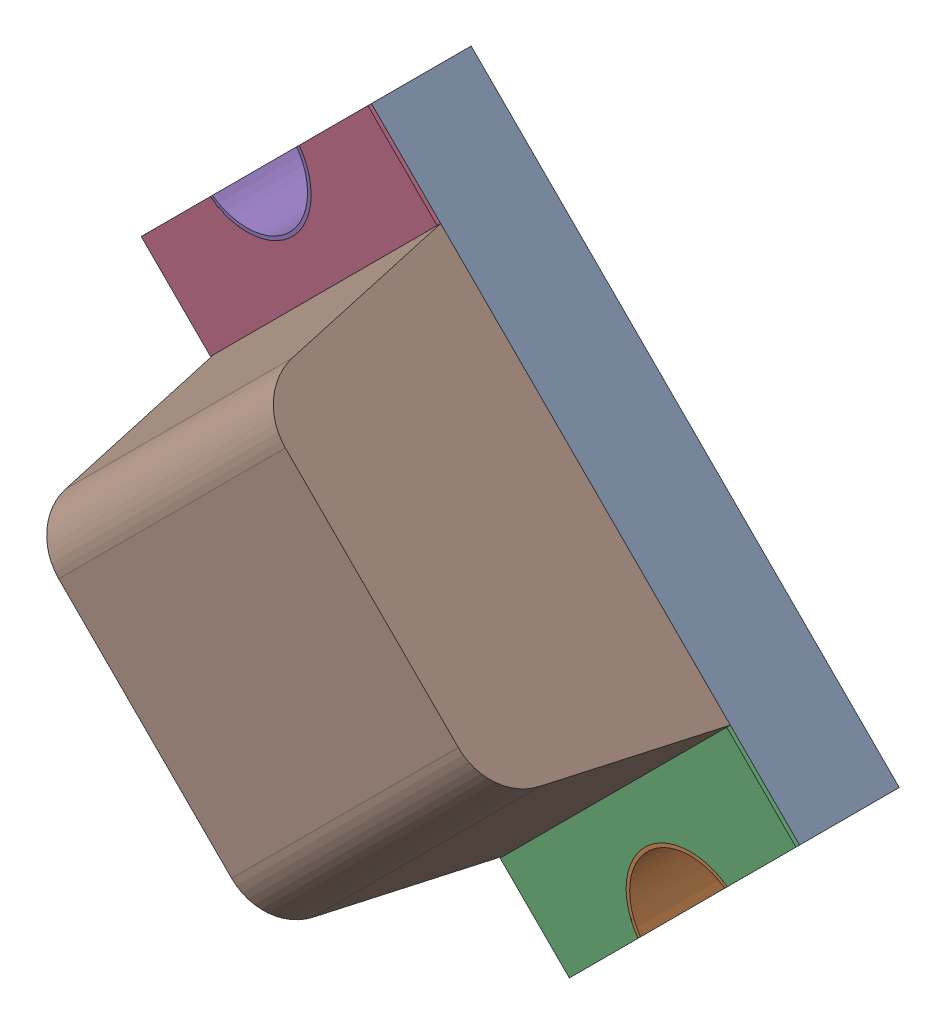
SolidWorks assembly D1K60, configuration 默认. Lengths in mm.
Overall size (1.84 1.84 0.9).
7 component instances, 6 part files, 0 mates.
Components (placement in the parent):
- LED-RED-0603-1: LED-RED-0603 [默认] at (-30.9986 26.3759 0) x (-0.707107 -0.707107 0) z (0 0 1) size (0.9 1.7 0.9)
  - User_Library-LTST-C190EKT_Pad-1: User_Library-LTST-C190EKT_Pad [默认] at origin size (0.9 1.7 0.28)
  - User_Library-LTST-C190EKT_Pad005-1: User_Library-LTST-C190EKT_Pad005 [默认] at origin size (0.35 0.15 0.31)
  - User_Library-LTST-C190EKT_Pad001-1: User_Library-LTST-C190EKT_Pad001 [默认] at origin size (0.9 1.7 0.01)
  - User_Library-LTST-C190EKT_Pad004-1: User_Library-LTST-C190EKT_Pad004 [默认] at origin size (0.35 0.15 0.31)
  - User_Library-LTST-C190EKT_Pad003-1: User_Library-LTST-C190EKT_Pad003 [默认] at origin size (0.8 1.7 0.02)
  - User_Library-LTST-C190EKT_Lens-1: User_Library-LTST-C190EKT_Lens [默认] at origin size (0.9 1.15 0.6)
